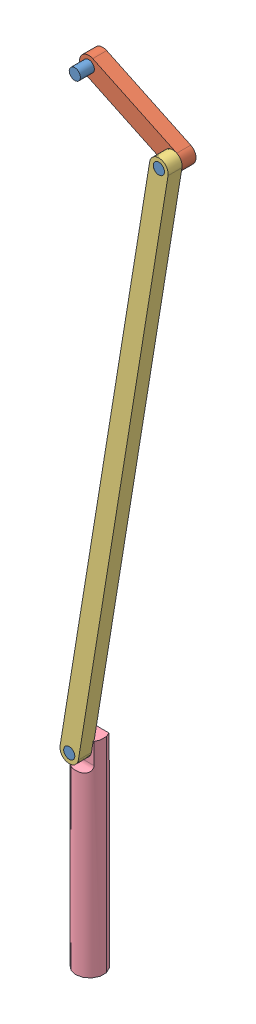
SolidWorks assembly FullAssembly, configuration Default. Lengths in mm.
Overall size (689.84 1749.87 74).
6 component instances, 4 part files, 12 mates.
Components (placement in the parent):
- Pin-1: Pin [Default] at origin size (24 24 60)
- Crank-1: Crank [Default] at (180.7211 -85.6731 0) x (-0.800624 0.599167 0) z (0 0 1) size (236.02 79.69 30)
- Pin-2: Pin [Default] at (-12 -1270.0964 0) size (24 24 60)
- Pin-3: Pin [Default] at (180.7211 -85.6731 0) size (24 24 60)
- Coupler-1: Coupler [Default] at (-12 -1270.0964 30) x (0.353282 0.935517 0) z (0 0 1) size (1216.13 278.14 30)
- Punch-1: Punch [Default] at (-12 -1500.0964 1) x (0 0 1) z (-1 0 0) size (60 440 60)
Mates (geometry in assembly coordinates):
- Concentric1: concentric aligned: cylinder of Pin-1 through (0 0 60) axis (0 0 -1) radius 12; cylinder of Crank-1 through (0 0 30) axis (0 0 -1) radius 12
- Coincident3: coincident aligned: plane of Pin-1 through (0 0 0) normal (0 0 -1); plane of Crank-1 through (-200 0 0) normal (0 0 -1)
- Concentric2: concentric aligned: cylinder of Crank-1 through (-200 0 30) axis (0 0 -1) radius 12; cylinder of Pin-3 through (-200 0 60) axis (0 0 -1) radius 12
- Coincident4: coincident aligned: plane of Crank-1 through (-200 0 0) normal (0 0 -1); plane of Pin-3 through (-200 0 0) normal (0 0 -1)
- Coincident5: coincident anti-aligned: cylinder of Pin-3 through (180.7211 -85.6731 60) axis (0 0 -1) radius 12; circle of Coupler-1
- Coincident6: coincident aligned: plane of Pin-3 through (-200 0 60) normal (0 0 1); plane of Coupler-1 through (-12 -1185.1818 60) normal (0 0 1)
- Concentric3: concentric aligned: cylinder of Pin-2 through (-12 -1185.1818 60) axis (0 0 -1) radius 12; cylinder of Coupler-1 through (-12 -1185.1818 60) axis (0 0 -1) radius 12
- Coincident8: coincident aligned: plane of Pin-2 through (-12 -1185.1818 60) normal (0 0 1); plane of Coupler-1 through (-12 -1185.1818 60) normal (0 0 1)
- Concentric4: concentric anti-aligned: cylinder of Pin-2 through (-12 -1185.1818 60) axis (0 0 -1) radius 12; cylinder of Punch-1 through (-12 -1185.1818 -14) axis (0 0 1) radius 12
- Coincident9: coincident aligned: plane of Pin-2 through (-12 -1185.1818 0) normal (0 0 -1); plane of Punch-1 through (-37.3772 -1165.1818 0) normal (0 0 -1)
- Distance1: distance = 20 mm: cylinder of assembly; point of assembly; cylinder of Punch-1 through (-12 -1240.7236 16) axis (0 1 0) radius 30
- Parallel1: parallel anti-aligned: plane of Punch-1 through (-12 -1605.1818 16) normal (0 -1 0)
